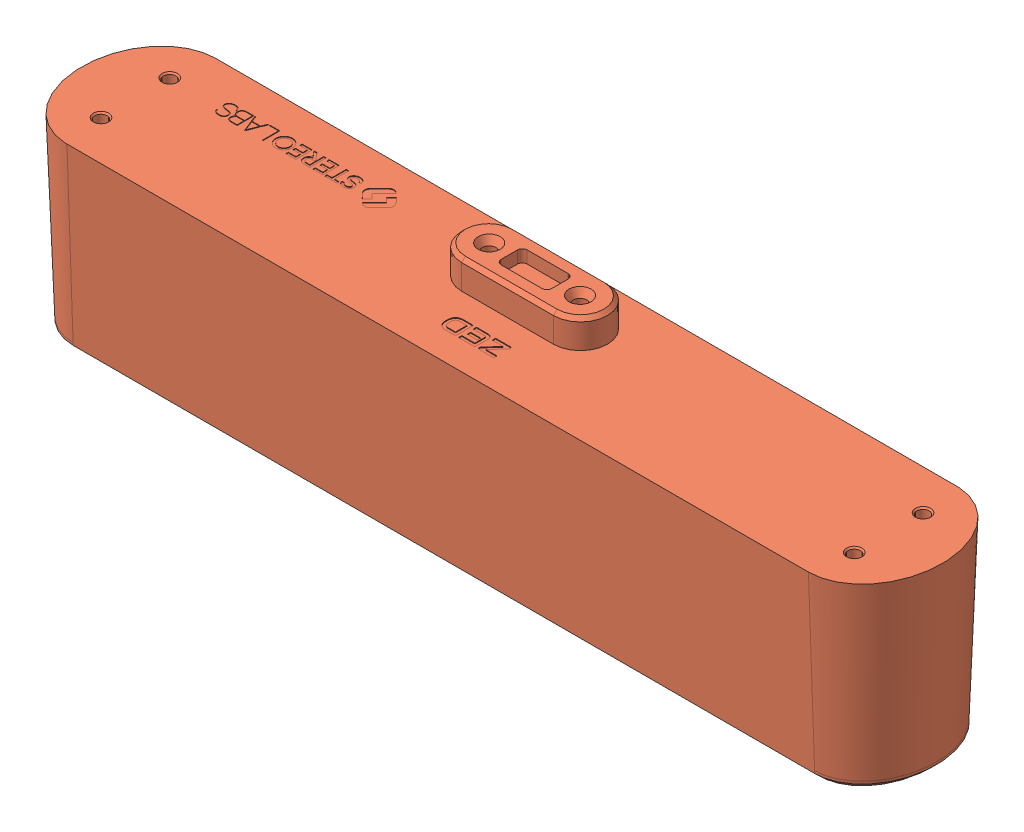
SolidWorks assembly ZED2i, configuration Default. Lengths in mm.
Overall size (175.3 43.1 32.76).
6 component instances, 4 part files, 0 mates.
Components (placement in the parent):
- ZED2i.step-1: ZED2i.step [Default] at origin size (175.3 43.1 32.76)
  - optic.step-1: optic.step [Default] at (-68.9685 6.689 8.643) size (18 15 18)
  - optic.step-2: optic.step [Default] at (51.0315 6.689 8.643) size (18 15 18)
  - ZED2_IP_Outer_with_lens.step-1: ZED2_IP_Outer_with_lens.step [Default] at origin size (175.3 43.1 32.76)
  - ZED2_IP_Outer_with_lens-0.step-1: ZED2_IP_Outer_with_lens-0.step [Default] at origin size (19.25 1 19.25)
  - ZED2_IP_Outer_with_lens-1.step-1: ZED2_IP_Outer_with_lens-1.step [Default] at origin size (19.25 1 19.25)
